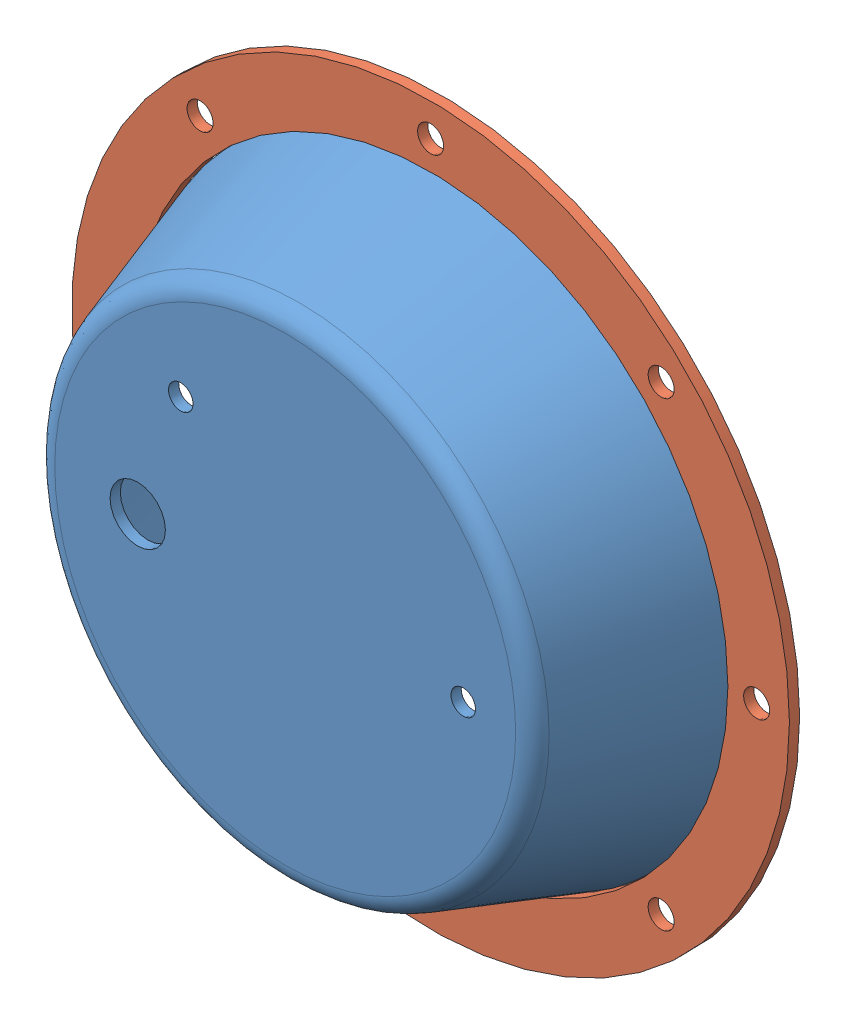
SolidWorks assembly Assemblage3, configuration Défaut. Lengths in mm.
Overall size (187.2 162.61 30.99).
2 component instances, 2 part files, 2 mates.
Components (placement in the parent):
- Rain Train 400. 002.C-1: Rain Train 400. 002.C [Défaut] at (-0.2761 5.1532 171.2993) size (155.81 115.92 30.99)
- Rain Train 400. 001A-1: Rain Train 400. 001A [Défaut] at (-0.2736 5.1931 142.9441) size (187.2 162.61 2)
Mates (geometry in assembly coordinates):
- Tangent1: tangent: circle of Rain Train 400. 002.C-1; cylinder of Rain Train 400. 001A-1 through (-0.2736 5.1931 140.9441) axis (0 0 1) radius 58
- Centre du profil1: profile center: circle of Rain Train 400. 002.C-1; circle of Rain Train 400. 001A-1
